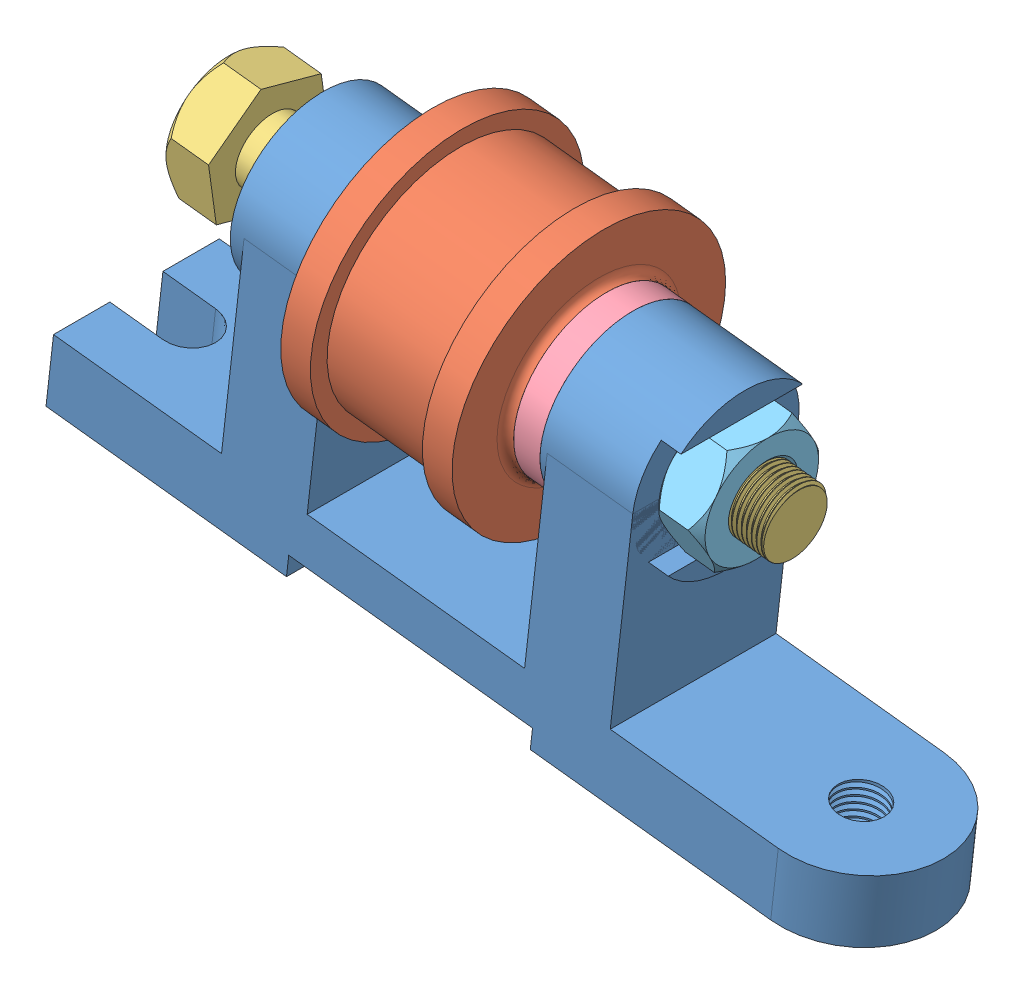
SolidWorks assembly PULLY_BRACKERT_ASSEMBLY, configuration Default. Lengths in mm.
Overall size (255.4 153.1 108.18).
6 component instances, 5 part files, 11 mates.
Components (placement in the parent):
- Bracket_PRT1-1: Bracket_PRT1 [Default] at (-76.2686 -18.5953 13.5825) x (0.113203 0.993572 0) z (0 0 1) size (105.75 245 50)
- Pully_PRT2-1: Pully_PRT2 [Default] at (-45.0394 52.3253 13.5825) x (0.045838 0.402314 -0.914354) z (0.103508 0.908476 0.404917) size (82 57 82)
- Shaft_PRT4-1: Shaft_PRT4 [Default] at (-144.0557 63.6068 13.5825) x (0.110191 0.967137 0.229139) z (0.025939 0.227666 -0.973394) size (43.18 174.63 34)
- Bush_PRT3-2: Bush_PRT3 [Default] at (-70.8722 55.2686 13.5825) x (0.09036 0.793078 -0.602381) z (-0.068191 -0.598509 -0.798209) size (50 34 50)
- Designation-1: Designation [Default] at (-2.3158 47.4576 13.5825) x (0 0 1) z (0.113203 0.993572 0) size (43.18 15.12 34)
- Bush_PRT3-3: Bush_PRT3 [Default] at (-62.9237 54.363 13.5825) x (-0.106276 -0.932776 0.344434) z (-0.038991 -0.34222 -0.938811) size (50 34 50)
Mates (geometry in assembly coordinates):
- Concentric3: concentric anti-aligned: cylinder of Bracket_PRT1-1 through (-142.4094 63.4192 13.5825) axis (0.993572 -0.113203 0) radius 10; cylinder of Shaft_PRT4-1 through (14.9158 45.4943 13.5825) axis (-0.993572 0.113203 0) radius 10
- Concentric4: concentric aligned: cylinder of Pully_PRT2-1 through (-45.0384 52.3252 13.5825) axis (-0.993572 0.113203 0) radius 17.5; cylinder of Shaft_PRT4-1 through (14.9158 45.4943 13.5825) axis (-0.993572 0.113203 0) radius 10
- Concentric5: concentric aligned: cylinder of Shaft_PRT4-1 through (14.9158 45.4943 13.5825) axis (-0.993572 0.113203 0) radius 10; cylinder of Bush_PRT3-3 through (-62.9227 54.3629 13.5825) axis (-0.993572 0.113203 0) radius 10
- Coincident11: coincident anti-aligned: plane of Bracket_PRT1-1 through (-96.7051 58.2119 13.5825) normal (0.993572 -0.113203 0); plane of Bush_PRT3-3 through (-99.362 34.8925 22.1933) normal (-0.993572 0.113203 0)
- Concentric7: concentric anti-aligned: cylinder of Shaft_PRT4-1 through (14.9158 45.4943 13.5825) axis (-0.993572 0.113203 0) radius 10; cylinder of Bush_PRT3-2 through (-70.8732 55.2687 13.5825) axis (0.993572 -0.113203 0) radius 10
- Coincident12: coincident anti-aligned: circle of Bracket_PRT1-1; plane of Bush_PRT3-2 through (-34.8318 71.2466 -1.477) normal (0.993572 -0.113203 0)
- Concentric8: concentric anti-aligned: cylinder of Pully_PRT2-1 through (-45.0384 52.3252 13.5825) axis (-0.993572 0.113203 0) radius 17.5; cylinder of Bush_PRT3-2 through (-37.06 51.4162 13.5825) axis (0.993572 -0.113203 0) radius 17.5
- Coincident14: coincident aligned: circle of Pully_PRT2-1; circle of Bush_PRT3-2
- Screw1: screw = 1 anti-aligned: cylinder of Shaft_PRT4-1 through (14.9158 45.4943 13.5825) axis (-0.993572 0.113203 0) radius 10; cylinder of Designation-1 through (-9.2718 48.2501 13.5825) axis (0.993572 -0.113203 0) radius 10
- Coincident15: coincident anti-aligned: plane of Bracket_PRT1-1 through (4.5765 63.7823 -11.4175) normal (-0.113203 -0.993572 0); plane of Designation-1 through (6.5637 63.5559 3.7675) normal (0.113203 0.993572 0)
- Coincident16: coincident anti-aligned: plane of Bracket_PRT1-1 through (-11.1952 31.3593 -11.4175) normal (0.993572 -0.113203 0); plane of Designation-1 through (-9.2708 48.25 13.5825) normal (-0.993572 0.113203 0)
